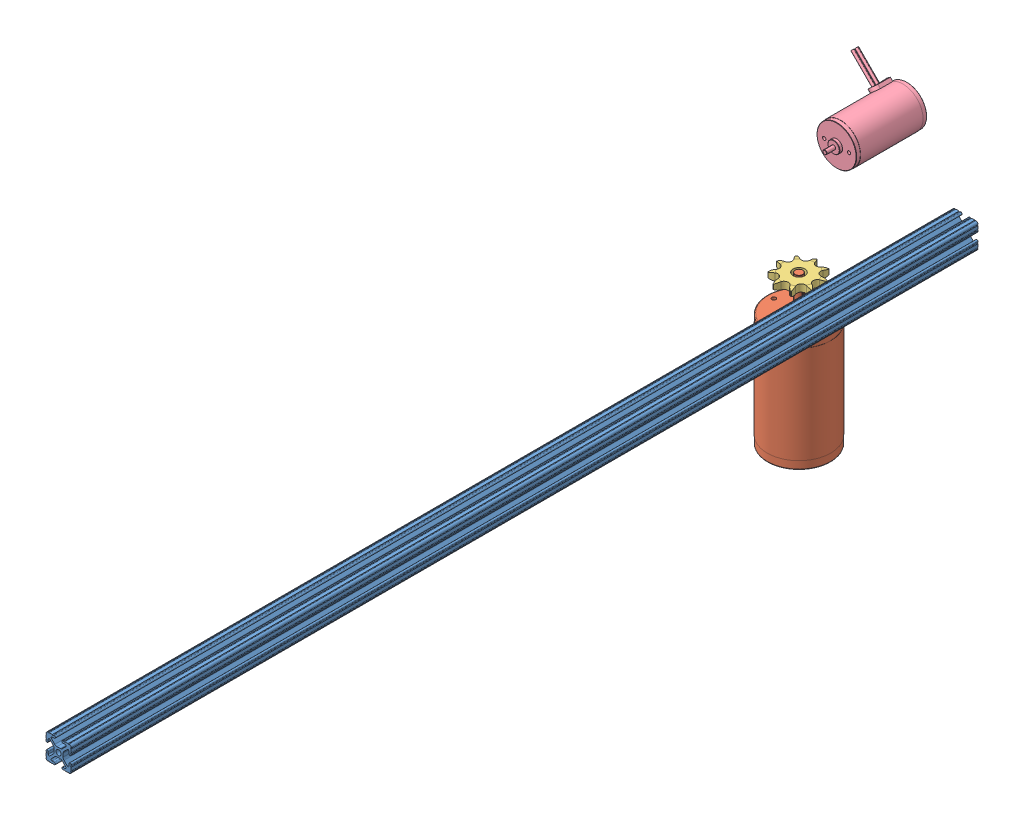
SolidWorks assembly Assem1, configuration Default. Lengths in mm.
Overall size (92.75 326.1 914.4).
4 component instances, 4 part files, 3 mates.
Components (placement in the parent):
- 8020Stock-1: 8020Stock [Default] at (177.2434 248.9824 943.4985) size (25.4 25.4 914.4)
- 2.5in CIM-1: 2.5in CIM [Default] at (99.8977 198.8199 264.4392) x (1 0 0) z (0 1 0) size (64.01 64.01 154.94)
- short pitch roller chain wheel_s_iso-1: short pitch roller chain wheel_s_iso [PreviewCfg] at (135.4577 253.4339 155.143) x (0 -1 0) z (0 0 1) size (8.29 43.26 43.93)
- Bag CIM-2: Bag CIM [Default] at (176.0064 385.6909 157.7409) size (59.11 59.11 84.5)
Mates (geometry in assembly coordinates):
- Parallel1: parallel: plane of 8020Stock-1 through (167.693 236.2824 29.0985) normal (0 -1 0); plane of 2.5in CIM-1 through (135.4577 217.8699 155.143) normal (0 1 0)
- Concentric1: concentric: cylinder of 2.5in CIM-1 through (135.4577 253.4339 155.143) axis (0 -1 0) radius 4; cylinder of short pitch roller chain wheel_s_iso-1 through (135.4577 244.0334 155.143) axis (0 1 0) radius 6
- Coincident2: coincident: plane of 2.5in CIM-1 through (135.4577 253.4339 155.143) normal (0 1 0); plane of short pitch roller chain wheel_s_iso-1 through (135.4577 253.4339 155.143) normal (0 1 0)
